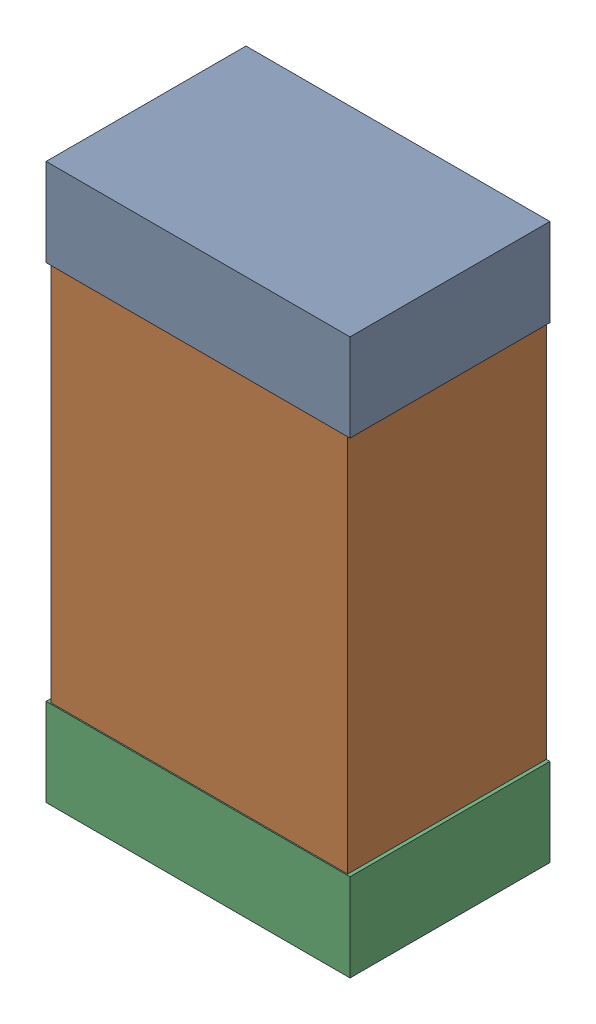
SolidWorks assembly Kanaloa_v2.0.0_Power_5, configuration Default. Lengths in mm.
Overall size (1.3 2.38 0.85).
6 component instances, 2 part files, 0 mates.
Components (placement in the parent):
- 330415056-1: 330415056 [Default] at (61.875 143.1 0) size (1.3 0.38 0.85)
  - Extruded_2-1: Extruded_2 [Default] at origin size (1.3 0.38 0.85)
- 352877008-1: 352877008 [Default] at (61.875 142.1 0) size (1.27 2.2 0.85)
  - Extruded_3-1: Extruded_3 [Default] at origin size (1.27 2.2 0.85)
- 330415056-2: 330415056 [Default] at (61.875 141.1 0) size (1.3 0.38 0.85)
  - Extruded_2-1: Extruded_2 [Default] at origin size (1.3 0.38 0.85)
